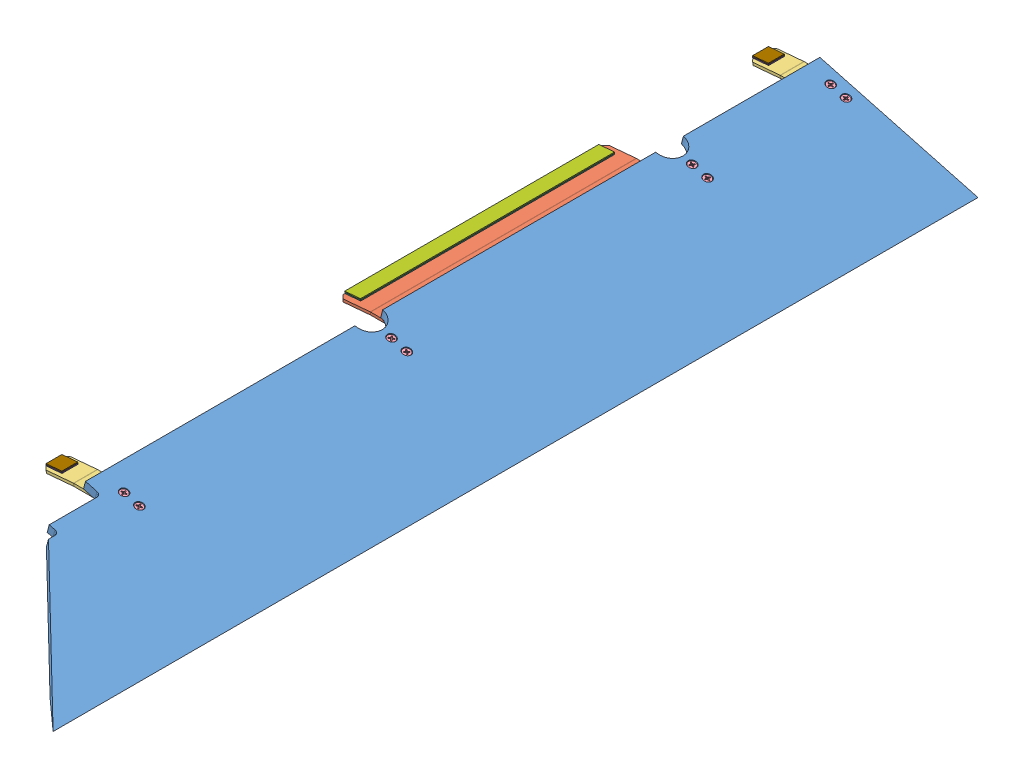
SolidWorks assembly GE-22017, configuration Default. Lengths in mm.
Overall size (328.85 67.77 1479.55).
32 component instances, 9 part files, 77 mates.
Components (placement in the parent):
- GE-22021-1: GE-22021 [Default] at origin size (256.21 67.77 1479.55)
- GE-22018-1: GE-22018 [Default] at (22.6565 49.2824 481.0125) x (0 0 -1) z (1 0 0) size (504.82 17.25 144.58)
- GE-22019-1: GE-22019 [Default] at (22.6565 49.2824 1149.35) x (0 0 -1) z (1 0 0) size (38.1 17.25 144.58)
- GE-22019-2: GE-22019 [Default] at (22.6565 49.2824 19.05) x (0 0 -1) z (1 0 0) size (38.1 17.25 144.58)
- flat_phil_.25_20_1.25-1: flat_phil_.25_20_1.25 [Default] at (60.5885 53.5322 1149.35) x (0.933013 -0.25 -0.258819) z (0.258819 0.965926 0) size (12.12 12.12 31.75)
- flat_phil_.25_20_1.25-2: flat_phil_.25_20_1.25 [Default] at (85.1231 46.9582 1149.35) x (0.854154 -0.22887 -0.466946) z (0.258819 0.965926 0) size (12.12 12.12 31.75)
- flat_phil_.25_20_1.25-4: flat_phil_.25_20_1.25 [Default] at (60.5885 53.5322 721.5187) x (0.72201 -0.193462 -0.664285) z (0.258819 0.965926 0) size (12.12 12.12 31.75)
- flat_phil_.25_20_1.25-6: flat_phil_.25_20_1.25 [Default] at (85.1231 46.9582 721.5187) x (0.543088 -0.14552 -0.82697) z (0.258819 0.965926 0) size (12.12 12.12 31.75)
- flat_phil_.25_20_1.25-8: flat_phil_.25_20_1.25 [Default] at (60.5885 53.5322 240.5062) x (0.338851 -0.090795 -0.936449) z (0.258819 0.965926 0) size (12.12 12.12 31.75)
- flat_phil_.25_20_1.25-10: flat_phil_.25_20_1.25 [Default] at (85.1231 46.9582 240.5062) x (0.139431 -0.03736 -0.989527) z (0.258819 0.965926 0) size (12.12 12.12 31.75)
- flat_phil_.25_20_1.25-12: flat_phil_.25_20_1.25 [Default] at (60.5885 53.5322 19.05) x (-0.028036 0.007512 -0.999579) z (0.258819 0.965926 0) size (12.12 12.12 31.75)
- flat_phil_.25_20_1.25-14: flat_phil_.25_20_1.25 [Default] at (85.1231 46.9582 19.05) x (-0.146973 0.039381 -0.988356) z (0.258819 0.965926 0) size (12.12 12.12 31.75)
- nylock_.25_20-1: nylock_.25_20 [Default] at (57.4071 41.6589 1149.35) x (-0.780768 0.209206 -0.588756) z (-0.568695 0.152381 0.808311) size (11.11 7.94 12.83)
- nylock_.25_20-2: nylock_.25_20 [Default] at (81.9416 35.0849 1149.35) x (-0.8876 0.237832 -0.394464) z (-0.381023 0.102095 0.918912) size (11.11 7.94 12.83)
- nylock_.25_20-4: nylock_.25_20 [Default] at (81.9416 35.0849 721.5187) x (-0.952842 0.255313 -0.164037) z (-0.158448 0.042456 0.986454) size (11.11 7.94 12.83)
- nylock_.25_20-6: nylock_.25_20 [Default] at (57.4071 41.6589 721.5187) x (-0.96265 0.257941 0.082286) z (0.079482 -0.021297 0.996609) size (11.11 7.94 12.83)
- nylock_.25_20-8: nylock_.25_20 [Default] at (81.9416 35.0849 240.5062) x (-0.916572 0.245595 0.315561) z (0.304808 -0.081673 0.948905) size (11.11 7.94 12.83)
- nylock_.25_20-10: nylock_.25_20 [Default] at (57.4071 41.6589 240.5062) x (-0.831142 0.222704 0.509516) z (0.492155 -0.131872 0.860461) size (11.11 7.94 12.83)
- nylock_.25_20-12: nylock_.25_20 [Default] at (57.4071 41.6589 19.05) x (-0.733461 0.19653 0.650701) z (0.628529 -0.168414 0.759334) size (11.11 7.94 12.83)
- nylock_.25_20-14: nylock_.25_20 [Default] at (81.9416 35.0849 19.05) x (-0.650289 0.174245 0.739434) z (0.714238 -0.19138 0.673229) size (11.11 7.94 12.83)
- Hook_1_16-1: Hook_1_16 [Default] at (-50.1321 44.8749 277.8125) x (0 0 1) z (-0.996195 -0.087156 0) size (406.4 1.59 25.4)
- Hook_1_16-2: Hook_1_16 [Default] at (9.8671 43.4277 277.8125) x (0 0 1) z (-1 0 0) size (406.4 1.59 25.4)
- Loop_1_16-1: Loop_1_16 [Default] at (-50.2704 46.4564 277.8125) x (0 0 1) z (-0.996195 -0.087156 0) size (406.4 1.59 25.4)
- Loop_1_16-2: Loop_1_16 [Default] at (9.8671 41.8402 277.8125) x (0 0 1) z (-1 0 0) size (406.4 1.59 25.4)
- Hook_1_1-1: Hook_1_1 [Default] at (-50.1321 44.8749 1162.05) x (0.996195 0.087156 0) z (0 0 1) size (25.4 1.59 25.4)
- Hook_1_1-2: Hook_1_1 [Default] at (9.8671 43.4277 1162.05) size (25.4 1.59 25.4)
- Hook_1_1-3: Hook_1_1 [Default] at (-50.1321 44.8749 31.75) x (0.996195 0.087156 0) z (0 0 1) size (25.4 1.59 25.4)
- Hook_1_1-4: Hook_1_1 [Default] at (9.8671 43.4277 31.75) size (25.4 1.59 25.4)
- Loop_1_1-1: Loop_1_1 [Default] at (-50.2704 46.4564 31.75) x (0.996195 0.087156 0) z (0 0 1) size (25.4 1.59 25.4)
- Loop_1_1-2: Loop_1_1 [Default] at (9.8671 41.8402 31.75) size (25.4 1.59 25.4)
- Loop_1_1-3: Loop_1_1 [Default] at (-50.2704 46.4564 1162.05) x (0.996195 0.087156 0) z (0 0 1) size (25.4 1.59 25.4)
- Loop_1_1-4: Loop_1_1 [Default] at (9.8671 41.8402 1162.05) size (25.4 1.59 25.4)
Mates (geometry in assembly coordinates):
- Coincident1: coincident anti-aligned: plane of GE-22021-1 through (22.225 55.5037 1479.55) normal (-0.258819 -0.965926 0); plane of BracketRampMid_v5-1 through (24.1829 54.9791 481.0125) normal (0.258819 0.965926 0)
- Concentric1: concentric aligned: cylinder of GE-22021-1 through (61.7986 58.048 721.5187) axis (0.258819 0.965926 0) radius 3.5712; cylinder of BracketRampMid_v5-1 through (58.5115 45.7807 721.5187) axis (0.258819 0.965926 0) radius 3.3735
- Concentric2: concentric aligned: cylinder of GE-22021-1 through (86.3331 51.474 721.5187) axis (0.258819 0.965926 0) radius 3.5712; cylinder of BracketRampMid_v5-1 through (83.0461 39.2067 721.5187) axis (0.258819 0.965926 0) radius 3.3735
- Coincident2: coincident anti-aligned: plane of GE-22021-1 through (22.225 55.5037 1479.55) normal (-0.258819 -0.965926 0); plane of BracketRampEdgeLeft-1 through (24.1829 54.9791 1149.35) normal (0.258819 0.965926 0)
- Concentric3: concentric aligned: cylinder of GE-22021-1 through (61.7986 58.048 1149.35) axis (0.258819 0.965926 0) radius 3.5712; cylinder of BracketRampEdgeLeft-1 through (58.5115 45.7807 1149.35) axis (0.258819 0.965926 0) radius 3.3735
- Concentric4: concentric aligned: cylinder of GE-22021-1 through (86.3331 51.474 1149.35) axis (0.258819 0.965926 0) radius 3.5712; cylinder of BracketRampEdgeLeft-1 through (83.0461 39.2067 1149.35) axis (0.258819 0.965926 0) radius 3.3735
- Coincident3: coincident anti-aligned: plane of GE-22021-1 through (22.225 55.5037 1479.55) normal (-0.258819 -0.965926 0); plane of BracketRampEdge-2 through (24.1829 54.9791 19.05) normal (0.258819 0.965926 0)
- Concentric5: concentric aligned: cylinder of GE-22021-1 through (61.7986 58.048 19.05) axis (0.258819 0.965926 0) radius 3.5712; cylinder of BracketRampEdge-2 through (58.5115 45.7807 19.05) axis (0.258819 0.965926 0) radius 3.3735
- Concentric6: concentric aligned: cylinder of GE-22021-1 through (86.3331 51.474 19.05) axis (0.258819 0.965926 0) radius 3.5712; cylinder of BracketRampEdge-2 through (83.0461 39.2067 19.05) axis (0.258819 0.965926 0) radius 3.3735
- Concentric7: concentric aligned: cylinder of GE-22021-1 through (61.7986 58.048 1149.35) axis (0.258819 0.965926 0) radius 3.5712; cylinder of flat_phil_.25_20_1.25-1 through (61.5944 57.2859 1149.35) axis (0.258819 0.965926 0) radius 3.175
- Coincident4: coincident aligned: cone of GE-22021-1 through (61.7986 58.048 1149.35) axis (-0.258819 -0.965926 0); cone of flat_phil_.25_20_1.25-1 through (61.5944 57.2859 1149.35) axis (-0.258819 -0.965926 0)
- Concentric8: concentric aligned: cylinder of GE-22021-1 through (86.3331 51.474 1149.35) axis (0.258819 0.965926 0) radius 3.5712; cylinder of flat_phil_.25_20_1.25-2 through (86.1289 50.7119 1149.35) axis (0.258819 0.965926 0) radius 3.175
- Coincident5: coincident aligned: cone of GE-22021-1 through (86.3331 51.474 1149.35) axis (-0.258819 -0.965926 0); cone of flat_phil_.25_20_1.25-2 through (86.1289 50.7119 1149.35) axis (-0.258819 -0.965926 0)
- Concentric9: concentric aligned: cylinder of GE-22021-1 through (61.7986 58.048 721.5187) axis (0.258819 0.965926 0) radius 3.5712; cylinder of flat_phil_.25_20_1.25-4 through (61.5944 57.2859 721.5187) axis (0.258819 0.965926 0) radius 3.175
- Coincident6: coincident aligned: cone of GE-22021-1 through (61.7986 58.048 721.5187) axis (-0.258819 -0.965926 0); cone of flat_phil_.25_20_1.25-4 through (61.5944 57.2859 721.5187) axis (-0.258819 -0.965926 0)
- Concentric10: concentric aligned: cylinder of GE-22021-1 through (86.3331 51.474 721.5187) axis (0.258819 0.965926 0) radius 3.5712; cylinder of flat_phil_.25_20_1.25-6 through (86.1289 50.7119 721.5187) axis (0.258819 0.965926 0) radius 3.175
- Coincident7: coincident aligned: cone of GE-22021-1 through (86.3331 51.474 721.5187) axis (-0.258819 -0.965926 0); cone of flat_phil_.25_20_1.25-6 through (86.1289 50.7119 721.5187) axis (-0.258819 -0.965926 0)
- Concentric11: concentric aligned: cylinder of GE-22021-1 through (61.7986 58.048 240.5062) axis (0.258819 0.965926 0) radius 3.5712; cylinder of flat_phil_.25_20_1.25-8 through (61.5944 57.2859 240.5062) axis (0.258819 0.965926 0) radius 3.175
- Coincident8: coincident aligned: cone of GE-22021-1 through (61.7986 58.048 240.5062) axis (-0.258819 -0.965926 0); cone of flat_phil_.25_20_1.25-8 through (61.5944 57.2859 240.5062) axis (-0.258819 -0.965926 0)
- Concentric12: concentric aligned: cylinder of GE-22021-1 through (86.3331 51.474 240.5062) axis (0.258819 0.965926 0) radius 3.5712; cylinder of flat_phil_.25_20_1.25-10 through (86.1289 50.7119 240.5062) axis (0.258819 0.965926 0) radius 3.175
- Coincident9: coincident aligned: cone of GE-22021-1 through (86.3331 51.474 240.5062) axis (-0.258819 -0.965926 0); cone of flat_phil_.25_20_1.25-10 through (86.1289 50.7119 240.5062) axis (-0.258819 -0.965926 0)
- Concentric13: concentric aligned: cylinder of GE-22021-1 through (61.7986 58.048 19.05) axis (0.258819 0.965926 0) radius 3.5712; cylinder of flat_phil_.25_20_1.25-12 through (61.5944 57.2859 19.05) axis (0.258819 0.965926 0) radius 3.175
- Coincident10: coincident aligned: cone of GE-22021-1 through (61.7986 58.048 19.05) axis (-0.258819 -0.965926 0); cone of flat_phil_.25_20_1.25-12 through (61.5944 57.2859 19.05) axis (-0.258819 -0.965926 0)
- Concentric14: concentric aligned: cylinder of GE-22021-1 through (86.3331 51.474 19.05) axis (0.258819 0.965926 0) radius 3.5712; cylinder of flat_phil_.25_20_1.25-14 through (86.1289 50.7119 19.05) axis (0.258819 0.965926 0) radius 3.175
- Coincident11: coincident aligned: cone of GE-22021-1 through (86.3331 51.474 19.05) axis (-0.258819 -0.965926 0); cone of flat_phil_.25_20_1.25-14 through (86.1289 50.7119 19.05) axis (-0.258819 -0.965926 0)
- Concentric15: concentric anti-aligned: cylinder of flat_phil_.25_20_1.25-1 through (61.5944 57.2859 1149.35) axis (0.258819 0.965926 0) radius 3.175; cylinder of nylock_.25_20-1 through (57.4071 41.6589 1149.35) axis (-0.258819 -0.965926 0) radius 3.175
- Coincident12: coincident anti-aligned: plane of GE-22019-1 through (23.0784 50.8573 1149.35) normal (-0.258819 -0.965926 0); plane of nylock_.25_20-1 through (57.4071 41.6589 1149.35) normal (0.258819 0.965926 0)
- Concentric16: concentric anti-aligned: cylinder of flat_phil_.25_20_1.25-2 through (86.1289 50.7119 1149.35) axis (0.258819 0.965926 0) radius 3.175; cylinder of nylock_.25_20-2 through (81.9416 35.0849 1149.35) axis (-0.258819 -0.965926 0) radius 3.175
- Coincident13: coincident anti-aligned: plane of GE-22019-1 through (23.0784 50.8573 1149.35) normal (-0.258819 -0.965926 0); plane of nylock_.25_20-2 through (81.9416 35.0849 1149.35) normal (0.258819 0.965926 0)
- Concentric17: concentric anti-aligned: cylinder of flat_phil_.25_20_1.25-6 through (86.1289 50.7119 721.5187) axis (0.258819 0.965926 0) radius 3.175; cylinder of nylock_.25_20-4 through (81.9416 35.0849 721.5187) axis (-0.258819 -0.965926 0) radius 3.175
- Coincident14: coincident anti-aligned: plane of GE-22018-1 through (23.0784 50.8573 481.0125) normal (-0.258819 -0.965926 0); plane of nylock_.25_20-4 through (81.9416 35.0849 721.5187) normal (0.258819 0.965926 0)
- Concentric18: concentric anti-aligned: cylinder of flat_phil_.25_20_1.25-4 through (61.5944 57.2859 721.5187) axis (0.258819 0.965926 0) radius 3.175; cylinder of nylock_.25_20-6 through (57.4071 41.6589 721.5187) axis (-0.258819 -0.965926 0) radius 3.175
- Coincident15: coincident anti-aligned: plane of GE-22018-1 through (23.0784 50.8573 481.0125) normal (-0.258819 -0.965926 0); plane of nylock_.25_20-6 through (57.4071 41.6589 721.5187) normal (0.258819 0.965926 0)
- Concentric19: concentric anti-aligned: cylinder of flat_phil_.25_20_1.25-10 through (86.1289 50.7119 240.5062) axis (0.258819 0.965926 0) radius 3.175; cylinder of nylock_.25_20-8 through (81.9416 35.0849 240.5062) axis (-0.258819 -0.965926 0) radius 3.175
- Coincident16: coincident anti-aligned: plane of GE-22018-1 through (23.0784 50.8573 481.0125) normal (-0.258819 -0.965926 0); plane of nylock_.25_20-8 through (81.9416 35.0849 240.5062) normal (0.258819 0.965926 0)
- Concentric20: concentric anti-aligned: cylinder of flat_phil_.25_20_1.25-8 through (61.5944 57.2859 240.5062) axis (0.258819 0.965926 0) radius 3.175; cylinder of nylock_.25_20-10 through (57.4071 41.6589 240.5062) axis (-0.258819 -0.965926 0) radius 3.175
- Coincident17: coincident anti-aligned: plane of GE-22018-1 through (23.0784 50.8573 481.0125) normal (-0.258819 -0.965926 0); plane of nylock_.25_20-10 through (57.4071 41.6589 240.5062) normal (0.258819 0.965926 0)
- Concentric21: concentric anti-aligned: cylinder of flat_phil_.25_20_1.25-12 through (61.5944 57.2859 19.05) axis (0.258819 0.965926 0) radius 3.175; cylinder of nylock_.25_20-12 through (57.4071 41.6589 19.05) axis (-0.258819 -0.965926 0) radius 3.175
- Coincident18: coincident anti-aligned: plane of GE-22019-2 through (23.0784 50.8573 19.05) normal (-0.258819 -0.965926 0); plane of nylock_.25_20-12 through (57.4071 41.6589 19.05) normal (0.258819 0.965926 0)
- Concentric22: concentric anti-aligned: cylinder of flat_phil_.25_20_1.25-14 through (86.1289 50.7119 19.05) axis (0.258819 0.965926 0) radius 3.175; cylinder of nylock_.25_20-14 through (81.9416 35.0849 19.05) axis (-0.258819 -0.965926 0) radius 3.175
- Coincident19: coincident anti-aligned: plane of GE-22019-2 through (23.0784 50.8573 19.05) normal (-0.258819 -0.965926 0); plane of nylock_.25_20-14 through (81.9416 35.0849 19.05) normal (0.258819 0.965926 0)
- Coincident20: coincident anti-aligned: plane of GE-22018-1 through (22.4862 51.2282 481.0125) normal (-0.087156 0.996195 0); plane of Hook_1_16-1 through (-50.1321 44.8749 277.8125) normal (0.087156 -0.996195 0)
- Coincident21: coincident aligned: plane of GE-22018-1 through (-50.1321 44.8749 693.7375) normal (-0.996195 -0.087156 0); plane of Hook_1_16-1 through (-50.2704 46.4564 277.8125) normal (-0.996195 -0.087156 0)
- Distance1: distance = 3.175 mm: plane of Hook_1_16-1 through (-50.2704 46.4564 277.8125) normal (0 0 -1); line of GE-22018-1 through (-50.1321 44.8749 274.6375) axis (0.087156 -0.996195 0)
- Coincident23: coincident anti-aligned: plane of GE-22018-1 through (22.6565 45.0152 481.0125) normal (0 -1 0); plane of Hook_1_16-2 through (9.8671 45.0152 277.8125) normal (0 1 0)
- Coincident24: coincident aligned: plane of Hook_1_16-1 through (-50.2704 46.4564 684.2125) normal (0 0 1); plane of Hook_1_16-2 through (9.8671 45.0152 684.2125) normal (0 0 1)
- Distance2: distance = 12.7 mm: point of Hook_1_16-2; moEndPointRef_w of GE-22018-1
- Coincident26: coincident anti-aligned: plane of Hook_1_16-1 through (-50.2704 46.4564 277.8125) normal (-0.087156 0.996195 0); plane of Loop_1_16-1 through (-50.2704 46.4564 277.8125) normal (0.087156 -0.996195 0)
- Coincident27: coincident aligned: plane of Hook_1_16-1 through (-50.2704 46.4564 277.8125) normal (-0.996195 -0.087156 0); plane of Loop_1_16-1 through (-50.4088 48.0378 277.8125) normal (-0.996195 -0.087156 0)
- Coincident28: coincident aligned: plane of Hook_1_16-1 through (-50.2704 46.4564 684.2125) normal (0 0 1); plane of Loop_1_16-1 through (-50.4088 48.0378 684.2125) normal (0 0 1)
- Coincident29: coincident anti-aligned: plane of Hook_1_16-2 through (9.8671 43.4277 277.8125) normal (0 -1 0); plane of Loop_1_16-2 through (9.8671 43.4277 277.8125) normal (0 1 0)
- Coincident30: coincident aligned: plane of Hook_1_16-2 through (9.8671 45.0152 277.8125) normal (-1 0 0); plane of Loop_1_16-2 through (9.8671 43.4277 277.8125) normal (-1 0 0)
- Coincident31: coincident aligned: plane of Hook_1_16-2 through (9.8671 45.0152 684.2125) normal (0 0 1); plane of Loop_1_16-2 through (9.8671 43.4277 684.2125) normal (0 0 1)
- Coincident32: coincident anti-aligned: plane of GE-22019-1 through (22.4862 51.2282 1149.35) normal (-0.087156 0.996195 0); plane of Hook_1_1-1 through (-50.1321 44.8749 1162.05) normal (0.087156 -0.996195 0)
- Coincident33: coincident: line of GE-22019-1 through (-49.7602 40.624 1162.05) axis (-0.087156 0.996195 0); plane of Hook_1_1-1 through (-50.2704 46.4564 1162.05) normal (0 0 1)
- Coincident34: coincident aligned: plane of GE-22019-1 through (-50.1321 44.8749 1168.4) normal (-0.996195 -0.087156 0); plane of Hook_1_1-1 through (-50.2704 46.4564 1162.05) normal (-0.996195 -0.087156 0)
- Coincident35: coincident anti-aligned: plane of GE-22019-1 through (22.6565 45.0152 1149.35) normal (0 -1 0); plane of Hook_1_1-2 through (9.8671 45.0152 1162.05) normal (0 1 0)
- Coincident36: coincident aligned: plane of Hook_1_1-1 through (-50.2704 46.4564 1162.05) normal (0 0 1); plane of Hook_1_1-2 through (9.8671 45.0152 1162.05) normal (0 0 1)
- Coincident38: coincident aligned: plane of Hook_1_16-2 through (9.8671 45.0152 277.8125) normal (-1 0 0); plane of Hook_1_1-2 through (9.8671 45.0152 1162.05) normal (-1 0 0)
- Coincident39: coincident anti-aligned: plane of GE-22019-2 through (22.4862 51.2282 19.05) normal (-0.087156 0.996195 0); plane of Hook_1_1-3 through (-50.1321 44.8749 31.75) normal (0.087156 -0.996195 0)
- Coincident40: coincident aligned: plane of GE-22019-2 through (-50.1321 44.8749 38.1) normal (-0.996195 -0.087156 0); plane of Hook_1_1-3 through (-50.2704 46.4564 31.75) normal (-0.996195 -0.087156 0)
- Coincident41: coincident: unknown of GE-22019-2; plane of Hook_1_1-3 through (-50.2704 46.4564 31.75) normal (0 0 1)
- Coincident42: coincident anti-aligned: plane of GE-22019-2 through (22.6565 45.0152 19.05) normal (0 -1 0); plane of Hook_1_1-4 through (9.8671 45.0152 31.75) normal (0 1 0)
- Coincident43: coincident aligned: plane of Hook_1_16-2 through (9.8671 45.0152 277.8125) normal (-1 0 0); plane of Hook_1_1-4 through (9.8671 45.0152 31.75) normal (-1 0 0)
- Coincident44: coincident aligned: plane of Hook_1_1-3 through (-50.2704 46.4564 31.75) normal (0 0 1); plane of Hook_1_1-4 through (9.8671 45.0152 31.75) normal (0 0 1)
- Coincident45: coincident anti-aligned: plane of Hook_1_1-3 through (-50.2704 46.4564 31.75) normal (-0.087156 0.996195 0); plane of Loop_1_1-1 through (-50.2704 46.4564 31.75) normal (0.087156 -0.996195 0)
- Coincident46: coincident aligned: plane of Hook_1_1-3 through (-50.2704 46.4564 31.75) normal (0 0 1); plane of Loop_1_1-1 through (-50.4088 48.0378 31.75) normal (0 0 1)
- Coincident47: coincident aligned: plane of Hook_1_1-3 through (-50.2704 46.4564 31.75) normal (-0.996195 -0.087156 0); plane of Loop_1_1-1 through (-50.4088 48.0378 31.75) normal (-0.996195 -0.087156 0)
- Coincident48: coincident anti-aligned: plane of Hook_1_1-4 through (9.8671 43.4277 31.75) normal (0 -1 0); plane of Loop_1_1-2 through (9.8671 43.4277 31.75) normal (0 1 0)
- Coincident49: coincident aligned: plane of Hook_1_1-4 through (9.8671 45.0152 31.75) normal (0 0 1); plane of Loop_1_1-2 through (9.8671 43.4277 31.75) normal (0 0 1)
- Coincident50: coincident aligned: plane of Hook_1_1-4 through (9.8671 45.0152 31.75) normal (-1 0 0); plane of Loop_1_1-2 through (9.8671 43.4277 31.75) normal (-1 0 0)
- Coincident51: coincident anti-aligned: plane of Hook_1_1-1 through (-50.2704 46.4564 1162.05) normal (-0.087156 0.996195 0); plane of Loop_1_1-3 through (-50.2704 46.4564 1162.05) normal (0.087156 -0.996195 0)
- Coincident52: coincident aligned: plane of Hook_1_1-1 through (-50.2704 46.4564 1162.05) normal (0 0 1); plane of Loop_1_1-3 through (-50.4088 48.0378 1162.05) normal (0 0 1)
- Coincident53: coincident aligned: plane of Hook_1_1-1 through (-50.2704 46.4564 1162.05) normal (-0.996195 -0.087156 0); plane of Loop_1_1-3 through (-50.4088 48.0378 1162.05) normal (-0.996195 -0.087156 0)
- Coincident54: coincident anti-aligned: plane of Hook_1_1-2 through (9.8671 43.4277 1162.05) normal (0 -1 0); plane of Loop_1_1-4 through (9.8671 43.4277 1162.05) normal (0 1 0)
- Coincident55: coincident aligned: plane of Hook_1_1-2 through (9.8671 45.0152 1162.05) normal (0 0 1); plane of Loop_1_1-4 through (9.8671 43.4277 1162.05) normal (0 0 1)
- Coincident56: coincident aligned: plane of Hook_1_1-2 through (9.8671 45.0152 1162.05) normal (-1 0 0); plane of Loop_1_1-4 through (9.8671 43.4277 1162.05) normal (-1 0 0)
